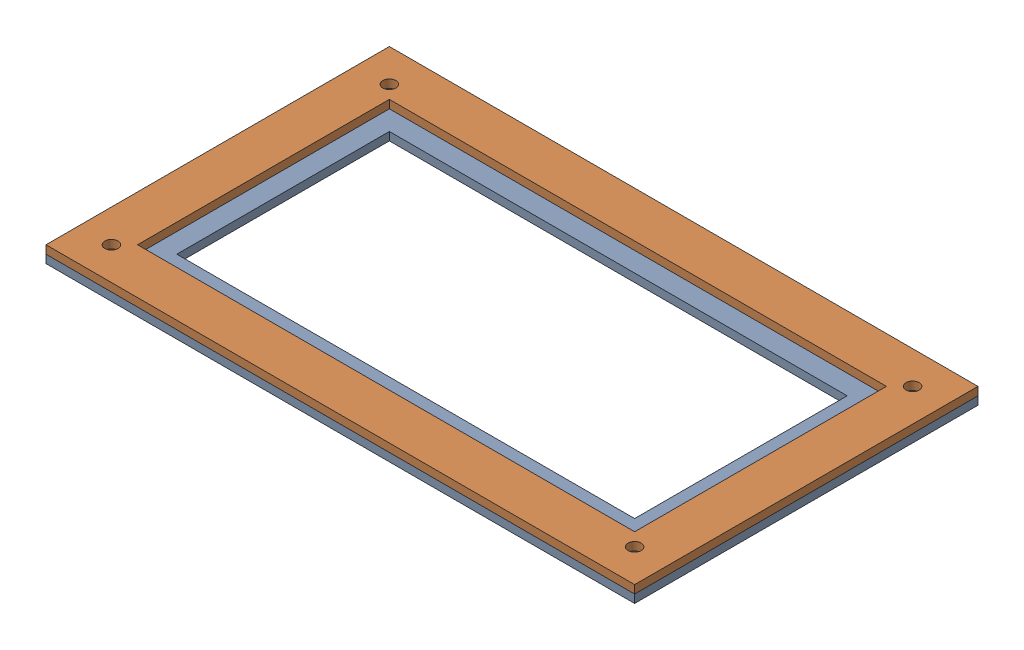
SolidWorks assembly plate_system_asm, configuration Default. Lengths in mm.
Overall size (360 10 210).
2 component instances, 2 part files, 3 mates.
Components (placement in the parent):
- fixed_base_plate_lower-1: fixed_base_plate_lower [Default] at (160.5048 170.6786 246.1418) size (360 5 210)
- fixed_base_plate_upper-1: fixed_base_plate_upper [Default] at (160.5048 175.6786 246.1418) size (360 5 210)
Mates (geometry in assembly coordinates):
- Coincident1: coincident anti-aligned: plane of fixed_base_plate_lower-1 through (160.5048 175.6786 246.1418) normal (0 1 0); plane of fixed_base_plate_upper-1 through (160.5048 175.6786 246.1418) normal (0 -1 0)
- Coincident2: coincident aligned: plane of fixed_base_plate_lower-1 through (340.5048 175.6786 351.1418) normal (1 0 0); plane of fixed_base_plate_upper-1 through (340.5048 180.6786 351.1418) normal (1 0 0)
- Coincident3: coincident aligned: plane of fixed_base_plate_lower-1 through (-19.4952 175.6786 141.1418) normal (0 0 -1); plane of fixed_base_plate_upper-1 through (-19.4952 180.6786 141.1418) normal (0 0 -1)
